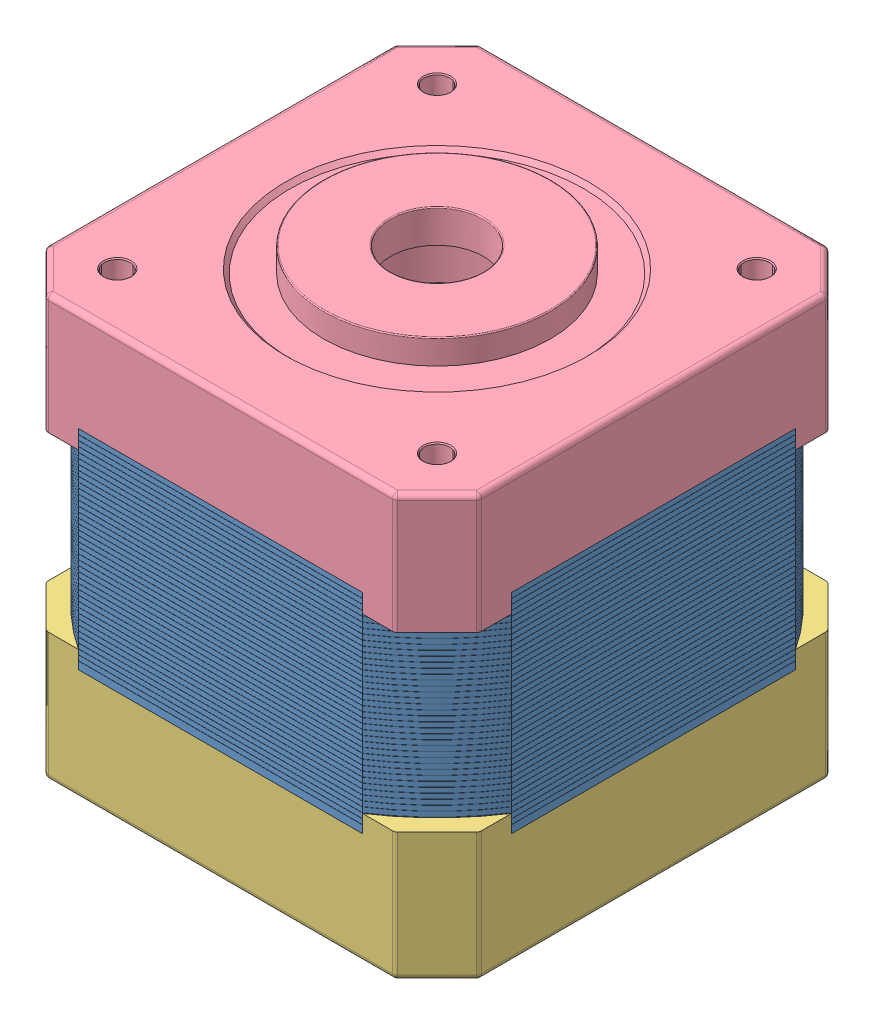
SolidWorks assembly Nema 17 17HS4401 SB, configuration По умолчанию. Lengths in mm.
Overall size (42 42.85 46.5).
8 component instances, 5 part files, 23 mates.
Components (placement in the parent):
- El_3 Nema 17 17HS4401-1: El_3 Nema 17 17HS4401 [По умолчанию] at origin size (42 20.25 42)
- El_5 Nema 17 17HS4401-1: El_5 Nema 17 17HS4401 [По умолчанию] at origin size (38 31.88 44.5)
- El_1 Nema 17 17HS4401-1: El_1 Nema 17 17HS4401 [По умолчанию] at (0 -20.925 0) size (42 12.5 42)
- El_2 Nema 17 17HS4401-1: El_2 Nema 17 17HS4401 [По умолчанию] at (0 19.925 0) x (-1 0 0) z (0 0 1) size (42 13.6 42)
- Винт Nema 17 17HS4401-1: Винт Nema 17 17HS4401 [Винт М3х28 ГОСТ 1491-80] at (-15.5 -18.305 15.5) x (1 0 0) z (0 -1 0) size (5 5 35)
- Винт Nema 17 17HS4401-2: Винт Nema 17 17HS4401 [Винт М3х28 ГОСТ 1491-80] at (15.5 -18.305 15.5) x (1 0 0) z (0 -1 0) size (5 5 35)
- Винт Nema 17 17HS4401-3: Винт Nema 17 17HS4401 [Винт М3х28 ГОСТ 1491-80] at (-15.5 -18.305 -15.5) x (1 0 0) z (0 -1 0) size (5 5 35)
- Винт Nema 17 17HS4401-4: Винт Nema 17 17HS4401 [Винт М3х28 ГОСТ 1491-80] at (15.5 -18.305 -15.5) x (1 0 0) z (0 -1 0) size (5 5 35)
Mates (geometry in assembly coordinates):
- Совпадение1: coincident aligned: plane of El_3 Nema 17 17HS4401-1 through (0 0 0) normal (0 1 0); plane of El_5 Nema 17 17HS4401-1 through (0 0 0) normal (0 1 0)
- Совпадение2: coincident aligned: plane of El_3 Nema 17 17HS4401-1 through (0 0 0) normal (0 0 1); plane of El_5 Nema 17 17HS4401-1 through (0 0 0) normal (0 0 1)
- Совпадение3: coincident aligned: plane of El_3 Nema 17 17HS4401-1 through (0 0 0) normal (1 0 0); plane of El_5 Nema 17 17HS4401-1 through (0 0 0) normal (1 0 0)
- Концентричный1: concentric aligned: cylinder of El_3 Nema 17 17HS4401-1 through (-15.5 -15.0747 15.5) axis (0 1 0) radius 1.75; cylinder of El_1 Nema 17 17HS4401-1 through (-15.5 -25.8747 15.5) axis (0 1 0) radius 1.75
- Концентричный2: concentric aligned: cylinder of El_3 Nema 17 17HS4401-1 through (15.5 -15.0747 -15.5) axis (0 1 0) radius 1.75; cylinder of El_1 Nema 17 17HS4401-1 through (15.5 -25.8747 -15.5) axis (0 1 0) radius 1.75
- Совпадение4: coincident anti-aligned: plane of El_3 Nema 17 17HS4401-1 through (0 -10.125 0) normal (0 -1 0); plane of El_1 Nema 17 17HS4401-1 through (0 -10.125 0) normal (0 1 0)
- Концентричный3: concentric anti-aligned: cylinder of El_1 Nema 17 17HS4401-1 through (0 -14.175 0) axis (0 -1 0) radius 8; cylinder of ? through (0 -18.125 0) axis (0 1 0) radius 8
- Совпадение5: coincident anti-aligned: plane of El_1 Nema 17 17HS4401-1 through (0 -18.425 0) normal (0 1 0); plane of ? through (3.0951 -18.425 -7.0505) normal (0 -1 0)
- Концентричный4: concentric anti-aligned: cylinder of El_3 Nema 17 17HS4401-1 through (-15.5 -15.0747 15.5) axis (0 1 0) radius 1.75; cylinder of El_2 Nema 17 17HS4401-1 through (-15.5 23.4605 15.5) axis (0 -1 0) radius 1.25
- Концентричный5: concentric anti-aligned: cylinder of El_3 Nema 17 17HS4401-1 through (15.5 -15.0747 -15.5) axis (0 1 0) radius 1.75; cylinder of El_2 Nema 17 17HS4401-1 through (15.5 23.4605 -15.5) axis (0 -1 0) radius 1.25
- Совпадение6: coincident anti-aligned: plane of El_3 Nema 17 17HS4401-1 through (0 10.125 0) normal (0 1 0); plane of El_2 Nema 17 17HS4401-1 through (0 10.125 0) normal (0 -1 0)
- Концентричный6: concentric aligned: cylinder of El_1 Nema 17 17HS4401-1 through (-15.5 -18.305 15.5) axis (0 -1 0) radius 3; cylinder of Винт Nema 17 17HS4401-1 through (-15.5 14.695 15.5) axis (0 -1 0) radius 1.5
- Концентричный7: concentric aligned: cylinder of El_1 Nema 17 17HS4401-1 through (15.5 -18.305 15.5) axis (0 -1 0) radius 3; cylinder of Винт Nema 17 17HS4401-2 through (15.5 14.695 15.5) axis (0 -1 0) radius 1.5
- Концентричный8: concentric aligned: cylinder of El_1 Nema 17 17HS4401-1 through (-15.5 -18.305 -15.5) axis (0 -1 0) radius 3; cylinder of Винт Nema 17 17HS4401-3 through (-15.5 14.695 -15.5) axis (0 -1 0) radius 1.5
- Концентричный9: concentric aligned: cylinder of El_1 Nema 17 17HS4401-1 through (15.5 -18.305 -15.5) axis (0 -1 0) radius 3; cylinder of Винт Nema 17 17HS4401-4 through (15.5 14.695 -15.5) axis (0 -1 0) radius 1.5
- Совпадение7: coincident aligned: plane of Винт Nema 17 17HS4401-3 through (-15.5 -20.305 -15.5) normal (0 -1 0); plane of Винт Nema 17 17HS4401-4 through (15.5 -20.305 -15.5) normal (0 -1 0)
- Совпадение8: coincident aligned: plane of Винт Nema 17 17HS4401-1 through (-15.5 -20.305 15.5) normal (0 -1 0); plane of Винт Nema 17 17HS4401-2 through (15.5 -20.305 15.5) normal (0 -1 0)
- Совпадение9: coincident aligned: plane of Винт Nema 17 17HS4401-1 through (-15.5 -20.305 15.5) normal (0 -1 0); plane of Винт Nema 17 17HS4401-3 through (-15.5 -20.305 -15.5) normal (0 -1 0)
- Параллельность1: parallel aligned: plane of El_1 Nema 17 17HS4401-1 through (-21 -8.425 21) normal (0 0 1); plane of Винт Nema 17 17HS4401-1 through (-15.5 -18.305 15.5) normal (0 0 1)
- Параллельность2: parallel aligned: plane of El_1 Nema 17 17HS4401-1 through (-21 -8.425 21) normal (0 0 1); plane of Винт Nema 17 17HS4401-2 through (15.5 -18.305 15.5) normal (0 0 1)
- Параллельность3: parallel aligned: plane of El_1 Nema 17 17HS4401-1 through (-21 -8.425 21) normal (0 0 1); plane of Винт Nema 17 17HS4401-3 through (-15.5 -18.305 -15.5) normal (0 0 1)
- Параллельность4: parallel aligned: plane of El_1 Nema 17 17HS4401-1 through (-21 -8.425 21) normal (0 0 1); plane of Винт Nema 17 17HS4401-4 through (15.5 -18.305 -15.5) normal (0 0 1)
- Совпадение14: coincident anti-aligned: plane of El_1 Nema 17 17HS4401-1 through (-15.5 -18.305 15.5) normal (0 -1 0); plane of Винт Nema 17 17HS4401-1 through (-15.5 -18.305 15.5) normal (0 1 0)
